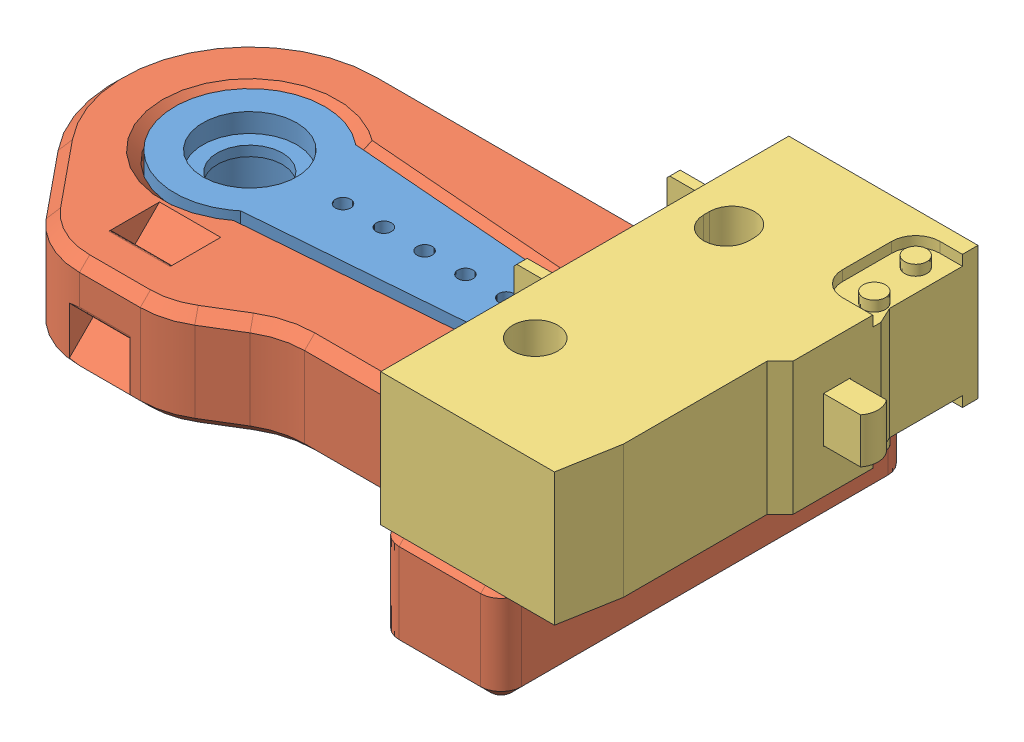
SolidWorks assembly ZProbeAssembly, configuration Default. Lengths in mm.
Overall size (37.45 11.45 19.99).
3 component instances, 3 part files, 3 mates.
Components (placement in the parent):
- Servo Horn-1: Servo Horn [Default] at (34.2536 11.8969 23.9402) size (19.66 4.12 7.35)
- ZProbeArm-1: ZProbeArm [Default] at origin size (31.66 4.95 19.95)
- SnapLimitSwitch-1: SnapLimitSwitch [Default] at (20.9623 16.7681 16.6426) x (0 0 1) z (0 1 0) size (19.99 14.86 6.5)
Mates (geometry in assembly coordinates):
- Coincident1: coincident anti-aligned: plane of ZProbeArm-1 through (0 13.5169 0) normal (0 1 0); plane of SnapLimitSwitch-1 through (20.9623 13.5169 26.6375) normal (0 -1 0)
- Concentric1: concentric anti-aligned: cylinder of ZProbeArm-1 through (23.3245 8.5669 21.4305) axis (0 1 0) radius 1.025; cylinder of SnapLimitSwitch-1 through (23.3245 20.0193 21.4305) axis (0 -1 0) radius 1.1049
- Parallel1: parallel anti-aligned: plane of ZProbeArm-1 through (26.8245 8.5669 0) normal (1 0 0); plane of SnapLimitSwitch-1 through (20.9623 20.0193 6.6477) normal (-1 0 0)
